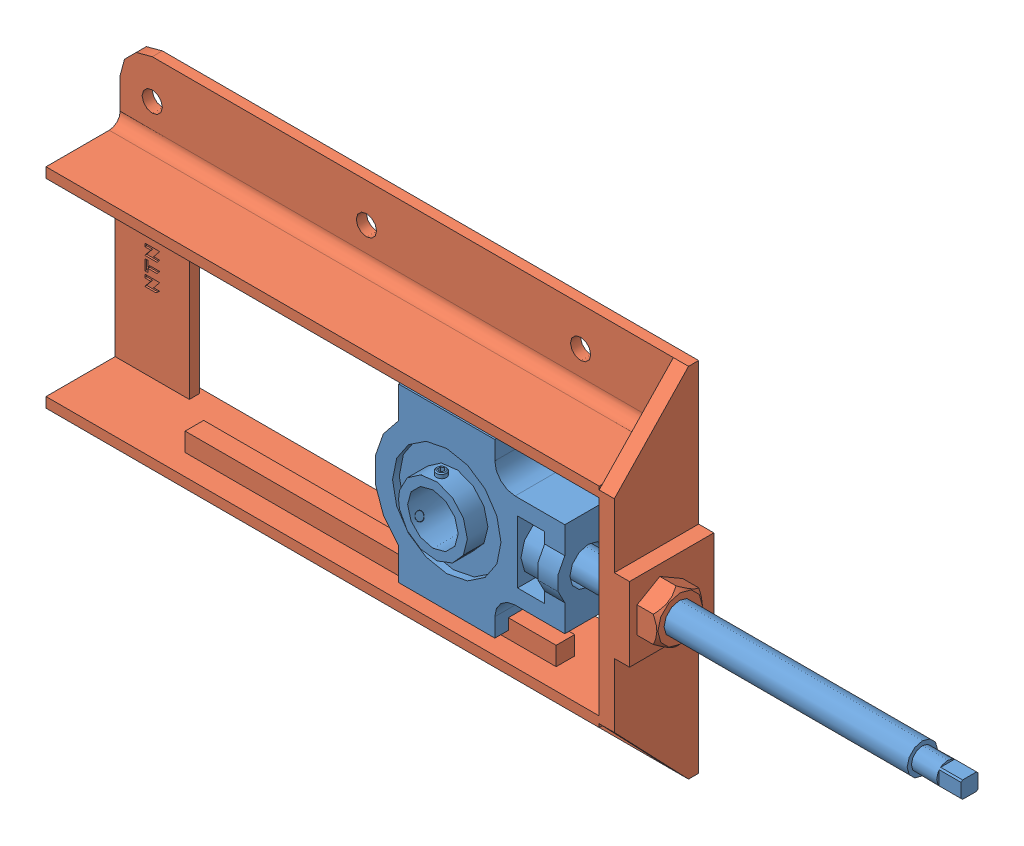
SolidWorks assembly UCT206-15D1(30,D10), configuration Default. Lengths in mm.
Overall size (530.14 212 54.7).
2 component instances, 2 part files, 4 mates.
Components (placement in the parent):
- UCT206-15D1UCTSU Housing-1: UCT206-15D1UCTSU Housing [Default] at (281.7009 -38.7003 227.9191) size (339 102 40.7)
- UCT206-15D1UCTSU Frame-1: UCT206-15D1UCTSU Frame [Default] at (144.557 -39.2003 227.4191) size (358 212 50)
Mates (geometry in assembly coordinates):
- Coincident3: coincident anti-aligned: plane of UCT206-15D1UCTSU Housing-1 through (253.2009 5.7997 221.9191) normal (0 0 1); plane of UCT206-15D1UCTSU Frame-1 through (337.557 5.7997 221.9191) normal (0 0 -1)
- Parallel2: parallel anti-aligned: plane of UCT206-15D1UCTSU Housing-1 through (310.2009 5.7997 233.9191) normal (0 0 -1); plane of UCT206-15D1UCTSU Frame-1 through (117.557 5.7997 232.9191) normal (0 0 1)
- Coincident5: coincident anti-aligned: plane of UCT206-15D1UCTSU Housing-1 through (253.2009 -89.7003 221.9191) normal (0 0 1); plane of UCT206-15D1UCTSU Frame-1 through (337.557 -95.2003 221.9191) normal (0 0 -1)
- Coincident6: coincident anti-aligned: plane of UCT206-15D1UCTSU Housing-1 through (253.2009 5.7997 221.9191) normal (0 1 0); plane of UCT206-15D1UCTSU Frame-1 through (117.557 5.7997 232.9191) normal (0 -1 0)
